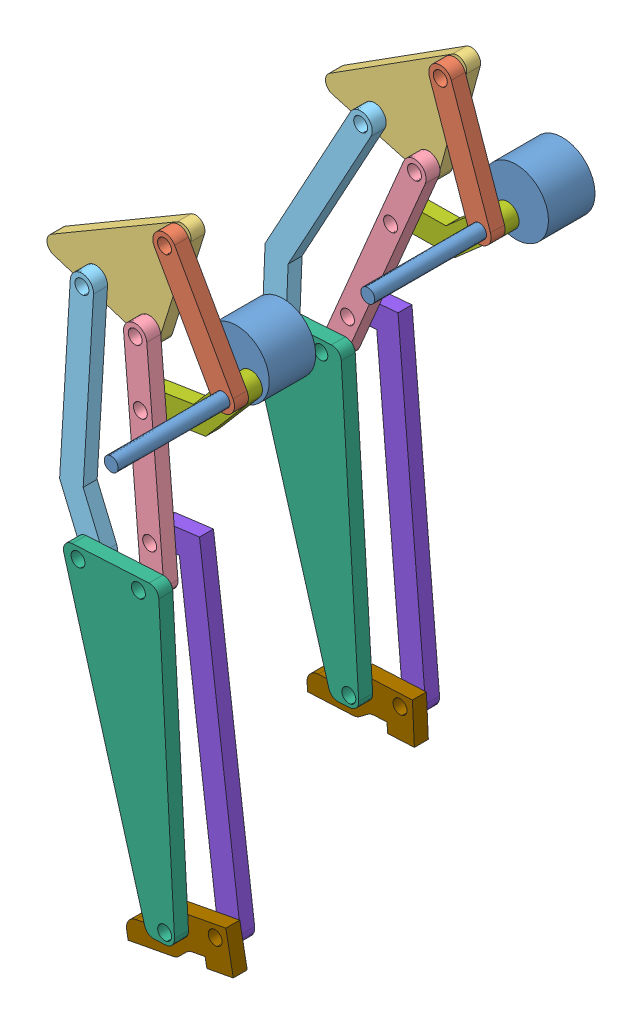
SolidWorks assembly humanoid_two legs, configuration Default. Lengths in mm.
Overall size (66.66 143.78 100).
20 component instances, 9 part files, 2 mates.
Components (placement in the parent):
- Assem1_humanoid-1: Assem1_humanoid [Default] at (58.455 119.8546 97.1754) size (48.06 143 40) (flexible)
  - crank^Assem1_humanoid-1: crank^Assem1_humanoid [Default] at (0 0 -10) x (0.800711 -0.599051 0) z (0 0 1) size (14 14 40) (virtual)
  - crank pin^Assem1_humanoid-1: crank pin^Assem1_humanoid [Default] at (3.0427 -2.2764 3) x (0.871558 0.490293 0) z (0 0 1) size (5 30.6 3) (virtual)
  - Part3^Assem1_humanoid-1: Part3^Assem1_humanoid [Default] at (-15.8 0 0) x (0.954071 -0.299581 0) z (0 0 1) size (24.98 27.13 3) (virtual)
  - Part4^Assem1_humanoid-1: Part4^Assem1_humanoid [Default] at (-15.8 0 3) x (0.99647 0.083952 0) z (0 0 1) size (5 49 3) (virtual)
  - Part5^Assem1_humanoid-1: Part5^Assem1_humanoid [Default] at (-27.2488 3.595 6) x (-0.998208 0.059837 0) z (0 0 -1) size (10.04 52.93 3) (virtual)
  - Part6^Assem1_humanoid-1: Part6^Assem1_humanoid [Default] at (-25.0867 -44.5552 6) x (0.998505 0.054655 0) z (0 0 1) size (20.53 65.66 3) (virtual)
  - Part7^Assem1_humanoid-1: Part7^Assem1_humanoid [Default] at (-14.6918 -13.1534 0) x (0.988147 0.153508 0) z (0 0 1) size (24.19 13.03 3) (virtual)
  - Part8^Assem1_humanoid-1: Part8^Assem1_humanoid [Default] at (-12.6938 -36.8694 0) x (0.991993 0.126292 0) z (0 0 1) size (10.59 72.6 3) (virtual)
  - Part1^Assem1_humanoid-1: Part1^Assem1_humanoid [Default] at (-6.4721 -104.7077 3) x (0.982607 0.185696 0) z (0 0 1) size (22.98 8.62 3) (virtual)
- Assem1_humanoid-2: Assem1_humanoid [Default] at (58.455 119.8546 37.1754) x (0.999308 -0.037202 0) z (0 0 1) size (61.58 137.72 40) (flexible)
  - crank^Assem1_humanoid-1: crank^Assem1_humanoid [Default] at (0 0 -10) x (-0.445724 -0.89517 0) z (0 0 1) size (14 14 40) (virtual)
  - crank pin^Assem1_humanoid-1: crank pin^Assem1_humanoid [Default] at (-1.6938 -3.4016 3) x (0.931515 0.363703 0) z (0 0 1) size (5 30.6 3) (virtual)
  - Part3^Assem1_humanoid-1: Part3^Assem1_humanoid [Default] at (-15.8 0 0) x (0.973578 -0.228355 0) z (0 0 1) size (24.98 27.13 3) (virtual)
  - Part4^Assem1_humanoid-1: Part4^Assem1_humanoid [Default] at (-15.8 0 3) x (0.935075 -0.354449 0) z (0 0 1) size (5 49 3) (virtual)
  - Part5^Assem1_humanoid-1: Part5^Assem1_humanoid [Default] at (-27.4829 2.7403 6) x (-0.895211 0.445642 0) z (0 0 -1) size (10.04 52.93 3) (virtual)
  - Part6^Assem1_humanoid-1: Part6^Assem1_humanoid [Default] at (-44.3332 -42.417 6) x (0.995189 0.097978 0) z (0 0 1) size (20.53 65.66 3) (virtual)
  - Part7^Assem1_humanoid-1: Part7^Assem1_humanoid [Default] at (-20.4787 -12.343 0) x (0.998838 0.048191 0) z (0 0 1) size (24.19 13.03 3) (virtual)
  - Part8^Assem1_humanoid-1: Part8^Assem1_humanoid [Default] at (-28.9146 -34.5978 0) x (0.992591 0.1215 0) z (0 0 1) size (10.59 72.6 3) (virtual)
  - Part1^Assem1_humanoid-1: Part1^Assem1_humanoid [Default] at (-23.1231 -101.7042 3) x (0.996313 0.085797 0) z (0 0 1) size (22.98 8.62 3) (virtual)
Mates (geometry in assembly coordinates):
- Concentric5: concentric aligned: cylinder of Assem1_humanoid-1/crank^Assem1_humanoid-1 through (58.455 119.8546 97.1754) axis (0 0 -1) radius 7; cylinder of Assem1_humanoid-2/crank^Assem1_humanoid-1 through (58.455 119.8546 37.1754) axis (0 0 -1) radius 7
- Distance2: distance = 50 mm anti-aligned: plane of Assem1_humanoid-1/crank^Assem1_humanoid-1 through (58.455 119.8546 87.1754) normal (0 0 -1); plane of Assem1_humanoid-2/crank^Assem1_humanoid-1 through (58.455 119.8546 37.1754) normal (0 0 1)
